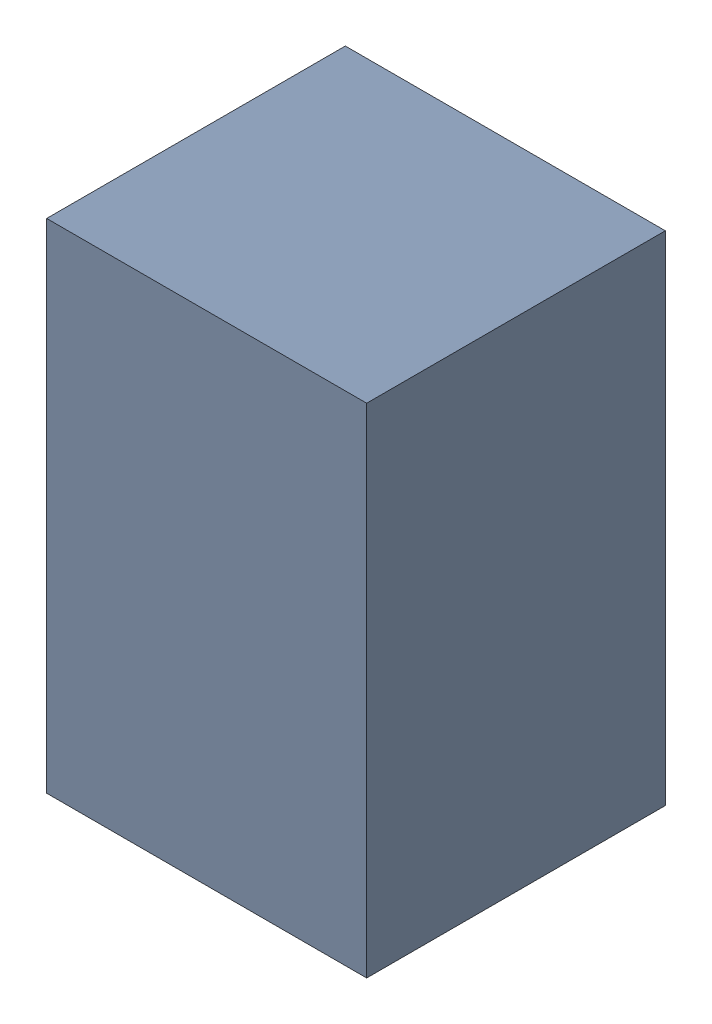
SolidWorks assembly C11., configuration Default. Lengths in mm.
Overall size (1.35 2.1 1.26).
2 component instances, 1 part files, 0 mates.
Components (placement in the parent):
- 407985696-1: 407985696 [Default] at (19.05 24.638 0.0127) size (1.35 2.1 1.26)
  - Extruded_1-1: Extruded_1 [Default] at origin size (1.35 2.1 1.26)
